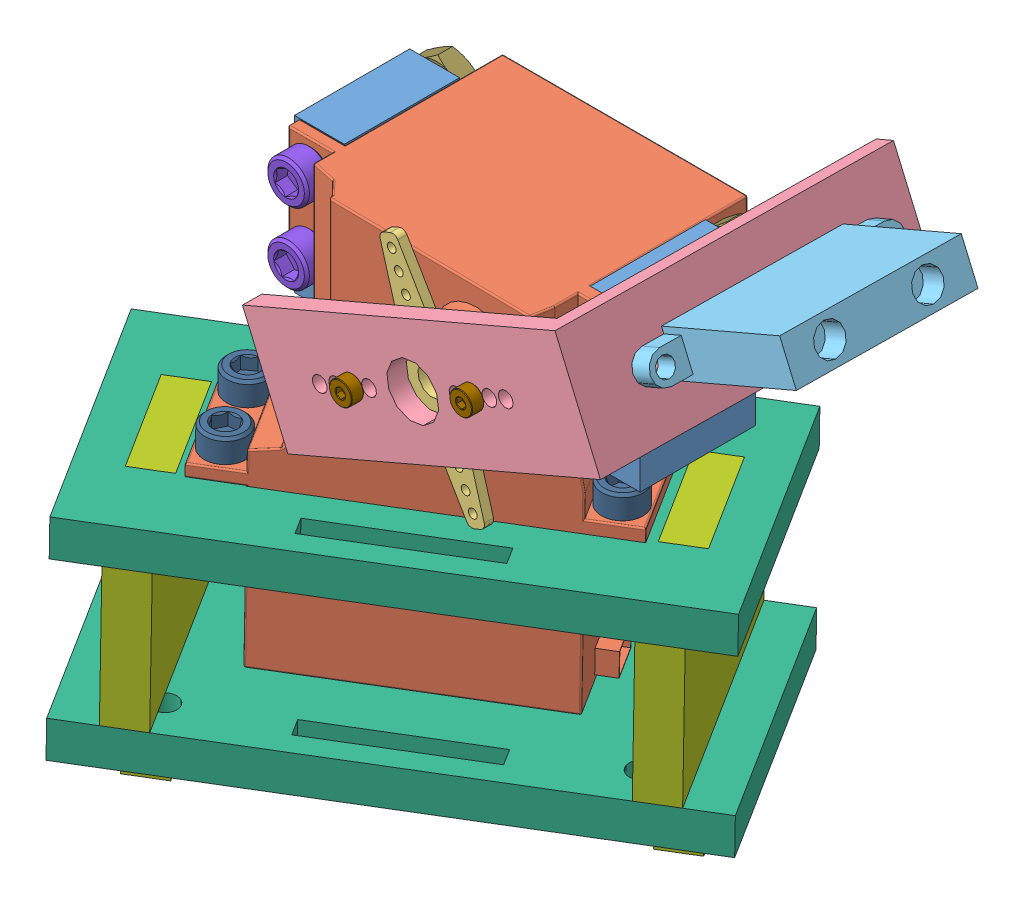
SolidWorks assembly Pan Tilt, configuration Default. Lengths in mm.
Overall size (116.12 101.24 80.83).
39 component instances, 12 part files, 90 mates.
Components (placement in the parent):
- Tilt Servo Mount-1: Tilt Servo Mount [Default] at (3.2915 33.3562 50.9879) size (57.15 25.37 39.37)
- servo motor-1: servo motor [Default] at (11.6735 58.7242 70.0379) x (1 0 0) z (0 -1 0) size (55.24 41.08 20.19)
- Servo Horn-1: Servo Horn [Default] at (42.5865 48.6277 85.0397) x (0.916481 0.399893 0.01215) z (0.399858 -0.916562 0.005301) size (38 5.5 38)
- Sensor Mount-1: Sensor Mount [Default] at (21.6417 29.1053 86.2622) x (0.916481 0.399893 0.01215) z (-0.013256 0 0.999912) size (57.15 19.05 55.24)
- Distance Sensor-1: Distance Sensor [Default] at (71.7666 57.4815 75.0766) x (0.013256 0 -0.999912) z (0.916481 0.399893 0.01215) size (41.7 7 21.62)
- Servo Horn-2: Servo Horn [Default] at (31.8665 31.8562 60.5128) size (38 5.5 38)
- servo motor-2: servo motor [Default] at (0.1726 17.2654 68.5885) x (0.845413 -0.013256 -0.533948) z (0.533995 0 0.845487) size (55.24 41.08 20.19)
- Base Plate-1: Base Plate [Default] at (10.8879 11.2334 85.7042) x (0.845413 -0.013256 -0.533948) z (0.533995 0 0.845487) size (82.55 6.03 43.18)
- Side Plate-1: Side Plate [Short] at (4.6513 11.4275 103.237) x (-0.011208 -0.999912 0.007079) z (0.533995 0 0.845487) size (44.13 6.03 43.18)
- Side Plate-2: Side Plate [Short] at (58.6571 10.5806 69.1279) x (-0.011208 -0.999912 0.007079) z (0.533995 0 0.845487) size (44.13 6.03 43.18)
- Base Plate-2: Base Plate [Breadclamp] at (10.5641 -17.6565 85.9087) x (0.845413 -0.013256 -0.533948) z (0.533995 0 0.845487) size (82.55 6.03 43.18)
- 91251A199_Black-Oxide Alloy Steel Socket Head Screw-1: 91251A199_Black-Oxide Alloy Steel Socket Head Screw [91251A199] at (8.1175 42.7222 61.4599) x (0.938495 -0.345293 0) z (0 0 1) size (6.86 6.86 30.18)
- 91251A199_Black-Oxide Alloy Steel Socket Head Screw-2: 91251A199_Black-Oxide Alloy Steel Socket Head Screw [91251A199] at (55.7425 42.7222 61.4599) x (0.998866 0.047604 0) z (0 0 1) size (6.86 6.86 30.18)
- 91251A199_Black-Oxide Alloy Steel Socket Head Screw-3: 91251A199_Black-Oxide Alloy Steel Socket Head Screw [91251A199] at (55.7425 54.5332 61.4599) x (0.697496 -0.716589 0) z (0 0 1) size (6.86 6.86 30.18)
- 91290A013_Black-Oxide Alloy Steel Socket Head Screw-2: 91290A013_Black-Oxide Alloy Steel Socket Head Screw [91290A013] at (52.6323 53.0265 87.8482) x (0.999912 0 0.013256) z (-0.013256 0 0.999912) size (3.8 3.8 8.09)
- 91290A013_Black-Oxide Alloy Steel Socket Head Screw-6: 91290A013_Black-Oxide Alloy Steel Socket Head Screw [91290A013] at (32.4697 44.2288 87.5808) x (0.999912 0 0.013256) z (-0.013256 0 0.999912) size (3.8 3.8 8.09)
- 91251A199_Black-Oxide Alloy Steel Socket Head Screw-5: 91251A199_Black-Oxide Alloy Steel Socket Head Screw [91251A199] at (8.1175 54.5332 61.4599) x (0.996492 -0.083694 0) z (0 0 1) size (6.86 6.86 30.18)
- 91251A190_Black-Oxide Alloy Steel Socket Head Screw-1: 91251A190_Black-Oxide Alloy Steel Socket Head Screw [91251A190] at (5.7172 17.843 84.013) x (0.091869 0.00602 0.995753) z (0.011208 0.999912 -0.007079) size (6.86 6.86 11.02)
- 91251A190_Black-Oxide Alloy Steel Socket Head Screw-2: 91251A190_Black-Oxide Alloy Steel Socket Head Screw [91251A190] at (-0.5898 17.843 74.0269) x (-0.38152 0.01082 0.924297) z (0.011208 0.999912 -0.007079) size (6.86 6.86 11.02)
- 91251A190_Black-Oxide Alloy Steel Socket Head Screw-3: 91251A190_Black-Oxide Alloy Steel Socket Head Screw [91251A190] at (39.673 17.2116 48.5976) x (0.655804 -0.002006 0.754928) z (0.011208 0.999912 -0.007079) size (6.86 6.86 11.02)
- 91251A190_Black-Oxide Alloy Steel Socket Head Screw-4: 91251A190_Black-Oxide Alloy Steel Socket Head Screw [91251A190] at (45.98 17.2116 58.5837) x (0.997237 -0.010658 0.073517) z (0.011208 0.999912 -0.007079) size (6.86 6.86 11.02)
- 91290A013_Black-Oxide Alloy Steel Socket Head Screw-7: 91290A013_Black-Oxide Alloy Steel Socket Head Screw [91290A013] at (14.8665 34.5312 60.5129) x (-0.912425 0 -0.409244) z (0 1 0) size (3.8 3.8 8.09)
- 91290A013_Black-Oxide Alloy Steel Socket Head Screw-8: 91290A013_Black-Oxide Alloy Steel Socket Head Screw [91290A013] at (48.8665 34.5312 60.5129) x (-0.885375 0 0.464877) z (0 1 0) size (3.8 3.8 8.09)
- 91290A013_Black-Oxide Alloy Steel Socket Head Screw-9: 91290A013_Black-Oxide Alloy Steel Socket Head Screw [91290A013] at (31.8665 34.5312 77.5128) x (-0.492181 0 -0.870493) z (0 1 0) size (3.8 3.8 8.09)
- 91290A013_Black-Oxide Alloy Steel Socket Head Screw-10: 91290A013_Black-Oxide Alloy Steel Socket Head Screw [91290A013] at (31.8665 34.5312 43.5129) x (-0.733437 0 -0.679757) z (0 1 0) size (3.8 3.8 8.09)
- 90592A004_Steel Hex Nut-1: 90592A004_Steel Hex Nut [90592A004] at (52.6784 53.0265 84.3735) x (0.82097 -0.570868 0.010884) z (-0.570818 -0.821042 -0.007568) size (4 1.91 4.62)
- 90592A004_Steel Hex Nut-2: 90592A004_Steel Hex Nut [90592A004] at (32.5158 44.2288 84.1062) x (-0.196615 -0.980477 -0.002607) z (-0.980391 0.196632 -0.012998) size (4 1.91 4.62)
- 90592A004_Steel Hex Nut-3: 90592A004_Steel Hex Nut [90592A004] at (48.8665 31.0562 60.5129) x (0.996971 0 -0.077772) z (-0.077772 0 -0.996971) size (4 1.91 4.62)
- 90592A004_Steel Hex Nut-4: 90592A004_Steel Hex Nut [90592A004] at (31.8665 31.0562 77.5128) x (1 0 0) z (0 0 -1) size (4 1.91 4.62)
- 90592A004_Steel Hex Nut-5: 90592A004_Steel Hex Nut [90592A004] at (14.8665 31.0562 60.5128) size (4 1.91 4.62)
- 90592A004_Steel Hex Nut-6: 90592A004_Steel Hex Nut [90592A004] at (31.8665 31.0562 43.5129) x (0.96042 0 0.278555) z (-0.278555 0 0.96042) size (4 1.91 4.62)
- 90480A009_Low-Strength Steel Hex Nut-1: 90480A009_Low-Strength Steel Hex Nut [90480A009] at (55.9965 54.7872 49.4004) x (0.990497 0.137534 0) z (0.137534 -0.990497 0) size (8.73 3.79 10.08)
- 90480A009_Low-Strength Steel Hex Nut-2: 90480A009_Low-Strength Steel Hex Nut [90480A009] at (55.9965 42.4682 49.4004) x (0.856607 -0.515969 0) z (-0.515969 -0.856607 0) size (8.73 3.79 10.08)
- 90480A009_Low-Strength Steel Hex Nut-3: 90480A009_Low-Strength Steel Hex Nut [90480A009] at (7.7365 54.7872 49.4004) x (0.999481 0.03222 0) z (0.03222 -0.999481 0) size (8.73 3.79 10.08)
- 90480A009_Low-Strength Steel Hex Nut-4: 90480A009_Low-Strength Steel Hex Nut [90480A009] at (7.7365 42.4682 49.4004) x (0.568434 -0.822729 0) z (-0.822729 -0.568434 0) size (8.73 3.79 10.08)
- 90480A009_Low-Strength Steel Hex Nut-5: 90480A009_Low-Strength Steel Hex Nut [90480A009] at (39.5816 9.0619 48.6553) x (0.997702 -0.011656 -0.066739) z (0.066815 0.006315 0.997745) size (8.73 3.79 10.08)
- 90480A009_Low-Strength Steel Hex Nut-6: 90480A009_Low-Strength Steel Hex Nut [90480A009] at (-0.8224 9.6949 74.0988) x (0.999937 -0.011208 0.000051) z (0.000029 0.007079 0.999975) size (8.73 3.79 10.08)
- 90480A009_Low-Strength Steel Hex Nut-7: 90480A009_Low-Strength Steel Hex Nut [90480A009] at (45.8887 9.0619 58.6414) x (0.999937 -0.011208 0.000051) z (0.000029 0.007079 0.999975) size (8.73 3.79 10.08)
- 90480A009_Low-Strength Steel Hex Nut-8: 90480A009_Low-Strength Steel Hex Nut [90480A009] at (5.6259 9.6932 84.0707) x (0.999937 -0.011208 0.000051) z (0.000029 0.007079 0.999975) size (8.73 3.79 10.08)
Mates (geometry in assembly coordinates):
- Coincident1: coincident anti-aligned: plane of Tilt Servo Mount-1 through (52.1865 38.5312 70.0379) normal (-1 0 0); plane of servo motor-1 through (52.1865 38.5312 11.4627) normal (1 0 0)
- Coincident2: coincident anti-aligned: plane of Tilt Servo Mount-1 through (11.5465 38.5312 70.0379) normal (0 1 0); plane of servo motor-1 through (31.8662 38.5312 11.4627) normal (0 -1 0)
- Coincident3: coincident anti-aligned: plane of Tilt Servo Mount-1 through (3.2915 33.3562 70.0379) normal (0 0 1); plane of servo motor-1 through (31.8662 38.5312 70.0379) normal (0 0 -1)
- Concentric1: concentric aligned: cylinder of servo motor-1 through (42.5865 48.6277 85.0397) axis (0.013256 0 -0.999912) radius 2.921; cylinder of Servo Horn-1 through (42.5666 48.6277 86.5396) axis (0.013256 0 -0.999912) radius 2.413
- Coincident4: coincident anti-aligned: plane of servo motor-1 through (4.1278 48.6263 84.5299) normal (-0.013256 0 0.999912); plane of Servo Horn-1 through (42.5865 48.6277 85.0397) normal (0.013256 0 -0.999912)
- Coincident5: coincident anti-aligned: plane of Sensor Mount-1; plane of Distance Sensor-1
- Concentric2: concentric aligned: cylinder of Sensor Mount-1 through (70.8068 60.6894 41.8885) axis (-0.916481 -0.399893 -0.01215) radius 1.5875; cylinder of Distance Sensor-1 through (73.7166 61.9591 41.9271) axis (-0.916481 -0.399893 -0.01215) radius 1.524
- Concentric3: concentric aligned: cylinder of Sensor Mount-1 through (70.3203 60.6894 78.5883) axis (-0.916481 -0.399893 -0.01215) radius 1.5875; cylinder of Distance Sensor-1 through (73.2301 61.9591 78.6269) axis (-0.916481 -0.399893 -0.01215) radius 1.524
- Concentric4: concentric aligned: cylinder of Servo Horn-1 through (35.2348 45.4285 86.4424) axis (0.013256 0 -0.999912) radius 0.75; cylinder of Sensor Mount-1 through (35.1927 45.4285 89.6171) axis (0.013256 0 -0.999912) radius 1.25
- Concentric5: concentric aligned: cylinder of Servo Horn-1 through (49.8985 51.8268 86.6368) axis (0.013256 0 -0.999912) radius 0.75; cylinder of Sensor Mount-1 through (49.8564 51.8268 89.8115) axis (0.013256 0 -0.999912) radius 1.25
- Coincident6: coincident anti-aligned: plane of Servo Horn-1 through (42.5666 48.6277 86.5396) normal (-0.013256 0 0.999912); plane of Sensor Mount-1 through (21.6417 29.1053 86.2622) normal (0.013256 0 -0.999912)
- Concentric8: concentric aligned: cylinder of Servo Horn-2 through (31.8665 33.3562 60.5128) axis (0 -1 0) radius 2.413; cylinder of servo motor-2 through (31.8665 31.8562 60.5128) axis (0 -1 0) radius 2.921
- Coincident7: coincident anti-aligned: plane of Servo Horn-2 through (31.8665 31.8562 60.5128) normal (0 -1 0); plane of servo motor-2 through (-0.652 31.8562 81.0526) normal (0 1 0)
- Concentric9: concentric aligned: cylinder of Tilt Servo Mount-1 through (39.8665 50.879 60.5129) axis (0 -1 0) radius 1.25; cylinder of Servo Horn-2 through (39.8665 33.3562 60.5128) axis (0 -1 0) radius 0.75
- Concentric10: concentric aligned: cylinder of Tilt Servo Mount-1 through (31.8665 50.879 52.5128) axis (0 -1 0) radius 1.25; cylinder of Servo Horn-2 through (31.8665 33.3562 52.5128) axis (0 -1 0) radius 0.75
- Coincident11: coincident anti-aligned: plane of Tilt Servo Mount-1 through (3.2915 33.3562 70.0379) normal (0 -1 0); plane of Servo Horn-2 through (31.8665 33.3562 60.5128) normal (0 1 0)
- Coincident12: coincident anti-aligned: plane of servo motor-2 through (28.0267 16.9977 74.8796) normal (-0.011208 -0.999912 0.007079); plane of Base Plate-1 through (10.9555 17.2654 85.6615) normal (0.011208 0.999912 -0.007079)
- Parallel8: parallel aligned: plane of servo motor-2 through (10.299 -41.3047 86.0761) normal (-0.845413 0.013256 0.533948); plane of Base Plate-1 through (-0.6226 17.5432 106.568) normal (-0.845413 0.013256 0.533948)
- Coincident14: coincident anti-aligned: plane of servo motor-2 through (27.3702 -41.5723 75.2942) normal (0.533995 0 0.845487); plane of Base Plate-1 through (10.9555 17.2654 85.6615) normal (-0.533995 0 -0.845487)
- Coincident15: coincident anti-aligned: plane of servo motor-2 through (10.299 -41.3047 86.0761) normal (-0.845413 0.013256 0.533948); plane of Base Plate-1 through (10.9555 17.2654 85.6615) normal (0.845413 -0.013256 -0.533948)
- Coincident17: coincident aligned: plane of Base Plate-1 through (10.9555 17.2654 85.6615) normal (0.011208 0.999912 -0.007079); plane of Side Plate-1 through (3.3762 17.3795 89.7725) normal (0.011208 0.999912 -0.007079)
- Coincident18: coincident anti-aligned: plane of Base Plate-1 through (-1.7237 17.4594 92.9935) normal (-0.533995 0 -0.845487); plane of Side Plate-1 through (3.3086 11.3475 89.8152) normal (0.533995 0 0.845487)
- Coincident21: coincident anti-aligned: plane of Base Plate-1 through (-11.8964 17.4594 76.887) normal (0.845413 -0.013256 -0.533948); plane of Side Plate-1 through (4.6513 11.4275 103.237) normal (-0.845413 0.013256 0.533948)
- Coincident22: coincident anti-aligned: plane of Base Plate-1 through (47.2094 16.5326 39.5568) normal (-0.845413 0.013256 0.533948); plane of Side Plate-2 through (63.7571 10.5007 65.9068) normal (0.845413 -0.013256 -0.533948)
- Coincident23: coincident aligned: plane of Base Plate-1 through (10.9555 17.2654 85.6615) normal (0.011208 0.999912 -0.007079); plane of Side Plate-2 through (57.382 16.5326 55.6633) normal (0.011208 0.999912 -0.007079)
- Coincident24: coincident anti-aligned: plane of Base Plate-1 through (57.382 16.5326 55.6633) normal (-0.533995 0 -0.845487); plane of Side Plate-2 through (57.3144 10.5007 55.706) normal (0.533995 0 0.845487)
- Coincident25: coincident anti-aligned: plane of Side Plate-1 through (9.495 -11.5105 100.1778) normal (-0.011208 -0.999912 0.007079); plane of Base Plate-2 through (10.6317 -11.6246 85.866) normal (0.011208 0.999912 -0.007079)
- Coincident26: coincident anti-aligned: plane of Side Plate-1 through (9.7513 11.3475 100.016) normal (0.845413 -0.013256 -0.533948); plane of Base Plate-2 through (-7.1202 -11.5105 73.8705) normal (-0.845413 0.013256 0.533948)
- Coincident27: coincident anti-aligned: plane of Side Plate-1 through (3.0524 -11.5105 89.977) normal (0.533995 0 0.845487); plane of Base Plate-2 through (-2.0476 -11.4305 93.1981) normal (-0.533995 0 -0.845487)
- Coincident28: coincident aligned: plane of Side Plate-1 through (2.8816 -26.7492 90.0849) normal (-0.011208 -0.999912 0.007079); plane of Base Plate-3 through (10.4609 -26.8632 85.9739) normal (-0.011208 -0.999912 0.007079)
- Concentric11: concentric aligned: cylinder of Base Plate-2 through (6.2678 -23.258 94.7056) axis (0.011208 0.999912 -0.007079) radius 2.0193; cylinder of Base Plate-3 through (6.1646 -32.4647 94.7708) axis (0.011208 0.999912 -0.007079) radius 2.0193
- Coincident29: coincident aligned: cylinder of Base Plate-2 through (-10.0084 -23.258 68.9352) axis (0.011208 0.999912 -0.007079) radius 2.0193; circle of Base Plate-3
- Concentric12: concentric anti-aligned: circle of servo motor-1; circle of 91251A199_Black-Oxide Alloy Steel Socket Head Screw-5
- Concentric13: concentric anti-aligned: cylinder of servo motor-1 through (8.1175 42.7222 62.1711) axis (0 0 1) radius 2.159; cylinder of 91251A199_Black-Oxide Alloy Steel Socket Head Screw-1 through (8.1175 42.7222 46.6771) axis (0 0 -1) radius 3.429
- Concentric14: concentric anti-aligned: cylinder of servo motor-1 through (55.7425 42.7222 62.1711) axis (0 0 1) radius 2.159; cylinder of 91251A199_Black-Oxide Alloy Steel Socket Head Screw-2 through (55.7425 42.7222 46.6771) axis (0 0 -1) radius 3.429
- Concentric15: concentric anti-aligned: cylinder of servo motor-1 through (55.7425 54.5332 62.1711) axis (0 0 1) radius 2.159; cylinder of 91251A199_Black-Oxide Alloy Steel Socket Head Screw-3 through (55.7425 54.5332 46.6771) axis (0 0 -1) radius 3.429
- Coincident30: coincident: plane of servo motor-1 through (31.8662 38.5312 72.0771) normal (0 0 1); point of 91251A199_Black-Oxide Alloy Steel Socket Head Screw-5
- Coincident31: coincident anti-aligned: plane of servo motor-1 through (31.8662 38.5312 72.0771) normal (0 0 1); plane of 91251A199_Black-Oxide Alloy Steel Socket Head Screw-1 through (9.1576 45.5493 72.0771) normal (0 0 -1)
- Coincident32: coincident anti-aligned: plane of servo motor-1 through (31.8662 38.5312 72.0771) normal (0 0 1); plane of 91251A199_Black-Oxide Alloy Steel Socket Head Screw-3 through (57.9011 56.6343 72.0771) normal (0 0 -1)
- Coincident33: coincident anti-aligned: plane of servo motor-1 through (31.8662 38.5312 72.0771) normal (0 0 1); plane of 91251A199_Black-Oxide Alloy Steel Socket Head Screw-2 through (55.5991 45.7312 72.0771) normal (0 0 -1)
- Concentric16: concentric aligned: cylinder of Sensor Mount-1 through (32.4432 44.2288 89.5807) axis (0.013256 0 -0.999912) radius 1.25; cylinder of 91290A013_Black-Oxide Alloy Steel Socket Head Screw-6 through (32.5228 44.2288 83.5812) axis (0.013256 0 -0.999912) radius 1.9
- Concentric17: concentric aligned: cylinder of Sensor Mount-1 through (52.6058 53.0265 89.848) axis (0.013256 0 -0.999912) radius 1.25; cylinder of 91290A013_Black-Oxide Alloy Steel Socket Head Screw-2 through (52.6854 53.0265 83.8485) axis (0.013256 0 -0.999912) radius 1.9
- Coincident34: coincident anti-aligned: plane of Sensor Mount-1 through (21.5996 29.1053 89.4369) normal (-0.013256 0 0.999912); plane of 91290A013_Black-Oxide Alloy Steel Socket Head Screw-2 through (52.6058 54.8265 89.848) normal (0.013256 0 -0.999912)
- Coincident35: coincident anti-aligned: plane of Sensor Mount-1 through (21.5996 29.1053 89.4369) normal (-0.013256 0 0.999912); plane of 91290A013_Black-Oxide Alloy Steel Socket Head Screw-6 through (32.4432 46.0288 89.5807) normal (0.013256 0 -0.999912)
- Concentric23: concentric anti-aligned: cylinder of Servo Horn-2 through (31.8665 33.3562 49.5128) axis (0 -1 0) radius 0.75; cylinder of 91290A013_Black-Oxide Alloy Steel Socket Head Screw-5 through (31.8665 37.9562 50.5129) axis (0 1 0) radius 1.9
- Coincident36: coincident anti-aligned: plane of Servo Horn-2 through (31.8665 31.8562 60.5128) normal (0 -1 0); circle of 91290A013_Black-Oxide Alloy Steel Socket Head Screw-5
- Concentric24: concentric anti-aligned: cylinder of servo motor-2 through (-0.6839 9.4465 74.0864) axis (0.011208 0.999912 -0.007079) radius 2.159; cylinder of 91251A190_Black-Oxide Alloy Steel Socket Head Screw-2 through (-0.6487 12.5856 74.0642) axis (-0.011208 -0.999912 0.007079) radius 3.429
- Concentric25: concentric anti-aligned: cylinder of servo motor-2 through (5.6231 9.4465 84.0724) axis (0.011208 0.999912 -0.007079) radius 2.159; cylinder of 91251A190_Black-Oxide Alloy Steel Socket Head Screw-1 through (5.6583 12.5856 84.0502) axis (-0.011208 -0.999912 0.007079) radius 3.429
- Concentric26: concentric anti-aligned: cylinder of servo motor-2 through (39.5789 8.8151 48.6571) axis (0.011208 0.999912 -0.007079) radius 2.159; cylinder of 91251A190_Black-Oxide Alloy Steel Socket Head Screw-3 through (39.6141 11.9543 48.6349) axis (-0.011208 -0.999912 0.007079) radius 3.429
- Concentric27: concentric anti-aligned: cylinder of servo motor-2 through (45.8859 8.8151 58.6431) axis (0.011208 0.999912 -0.007079) radius 2.159; cylinder of 91251A190_Black-Oxide Alloy Steel Socket Head Screw-4 through (45.9211 11.9543 58.6209) axis (-0.011208 -0.999912 0.007079) radius 3.429
- Coincident40: coincident anti-aligned: plane of servo motor-2 through (28.0496 19.0368 74.8652) normal (0.011208 0.999912 -0.007079); circle of 91251A190_Black-Oxide Alloy Steel Socket Head Screw-4
- Coincident41: coincident anti-aligned: plane of servo motor-2 through (28.0496 19.0368 74.8652) normal (0.011208 0.999912 -0.007079); circle of 91251A190_Black-Oxide Alloy Steel Socket Head Screw-3
- Coincident42: coincident anti-aligned: plane of servo motor-2 through (28.0496 19.0368 74.8652) normal (0.011208 0.999912 -0.007079); circle of 91251A190_Black-Oxide Alloy Steel Socket Head Screw-2
- Coincident43: coincident anti-aligned: plane of servo motor-2 through (28.0496 19.0368 74.8652) normal (0.011208 0.999912 -0.007079); circle of 91251A190_Black-Oxide Alloy Steel Socket Head Screw-1
- Concentric28: concentric anti-aligned: cylinder of Tilt Servo Mount-1 through (31.8665 36.5312 43.5129) axis (0 1 0) radius 2; cylinder of 91290A013_Black-Oxide Alloy Steel Socket Head Screw-10 through (31.8665 30.5312 43.5129) axis (0 -1 0) radius 1.9
- Coincident45: coincident anti-aligned: plane of Tilt Servo Mount-1 through (31.8665 36.5312 43.5129) normal (0 1 0); plane of 91290A013_Black-Oxide Alloy Steel Socket Head Screw-10 through (30.6429 36.5312 44.833) normal (0 -1 0)
- Concentric29: concentric anti-aligned: cylinder of Tilt Servo Mount-1 through (48.8665 36.5312 60.5129) axis (0 1 0) radius 2; cylinder of 91290A013_Black-Oxide Alloy Steel Socket Head Screw-8 through (48.8665 30.5312 60.5129) axis (0 -1 0) radius 1.9
- Concentric30: concentric anti-aligned: cylinder of Tilt Servo Mount-1 through (31.8665 36.5312 77.5128) axis (0 1 0) radius 2; cylinder of 91290A013_Black-Oxide Alloy Steel Socket Head Screw-9 through (31.8665 30.5312 77.5128) axis (0 -1 0) radius 1.9
- Concentric31: concentric anti-aligned: cylinder of Tilt Servo Mount-1 through (14.8665 36.5312 60.5129) axis (0 1 0) radius 2; cylinder of 91290A013_Black-Oxide Alloy Steel Socket Head Screw-7 through (14.8665 30.5312 60.5129) axis (0 -1 0) radius 1.9
- Coincident46: coincident anti-aligned: plane of Tilt Servo Mount-1 through (14.8665 36.5312 60.5129) normal (0 1 0); plane of 91290A013_Black-Oxide Alloy Steel Socket Head Screw-7 through (14.1298 36.5312 62.1552) normal (0 -1 0)
- Coincident47: coincident anti-aligned: plane of Tilt Servo Mount-1 through (31.8665 36.5312 77.5128) normal (0 1 0); plane of 91290A013_Black-Oxide Alloy Steel Socket Head Screw-9 through (30.2996 36.5312 78.3988) normal (0 -1 0)
- Coincident48: coincident anti-aligned: plane of Tilt Servo Mount-1 through (48.8665 36.5312 60.5129) normal (0 1 0); plane of 91290A013_Black-Oxide Alloy Steel Socket Head Screw-8 through (49.7032 36.5312 62.1065) normal (0 -1 0)
- Concentric32: concentric aligned: circle of 91290A013_Black-Oxide Alloy Steel Socket Head Screw-8; circle of 90592A004_Steel Hex Nut-3
- Coincident49: coincident anti-aligned: plane of Servo Horn-2 through (31.8665 31.8562 60.5128) normal (0 -1 0); plane of 90592A004_Steel Hex Nut-3 through (46.9623 31.8562 61.8196) normal (0 1 0)
- Concentric33: concentric aligned: circle of Tilt Servo Mount-1; circle of 90592A004_Steel Hex Nut-6
- Coincident51: coincident anti-aligned: plane of Servo Horn-2 through (31.8665 31.8562 60.5128) normal (0 -1 0); plane of 90592A004_Steel Hex Nut-6 through (30.2673 31.8562 41.8468) normal (0 1 0)
- Concentric34: concentric aligned: circle of Servo Horn-2; circle of 90592A004_Steel Hex Nut-5
- Coincident52: coincident anti-aligned: plane of Servo Horn-2 through (31.8665 31.8562 60.5128) normal (0 -1 0); plane of 90592A004_Steel Hex Nut-5 through (12.8665 31.8562 59.3581) normal (0 1 0)
- Concentric35: concentric aligned: circle of 91290A013_Black-Oxide Alloy Steel Socket Head Screw-9; circle of 90592A004_Steel Hex Nut-4
- Coincident54: coincident anti-aligned: plane of Servo Horn-2 through (31.8665 31.8562 60.5128) normal (0 -1 0); plane of 90592A004_Steel Hex Nut-4 through (29.8665 31.8562 78.6675) normal (0 1 0)
- Concentric36: concentric anti-aligned: cylinder of 91290A013_Black-Oxide Alloy Steel Socket Head Screw-6 through (32.5228 44.2288 83.5812) axis (0.013256 0 -0.999912) radius 1.9; circle of 90592A004_Steel Hex Nut-2
- Concentric37: concentric anti-aligned: cylinder of 91290A013_Black-Oxide Alloy Steel Socket Head Screw-2 through (52.6854 53.0265 83.8485) axis (0.013256 0 -0.999912) radius 1.9; circle of 90592A004_Steel Hex Nut-1
- Coincident55: coincident anti-aligned: plane of Servo Horn-1 through (42.5865 48.6277 85.0397) normal (0.013256 0 -0.999912); plane of 90592A004_Steel Hex Nut-1 through (51.685 55.1163 85.1604) normal (-0.013256 0 0.999912)
- Coincident56: coincident anti-aligned: plane of Servo Horn-1 through (42.5865 48.6277 85.0397) normal (0.013256 0 -0.999912); plane of 90592A004_Steel Hex Nut-2 through (34.0305 45.9627 84.9263) normal (-0.013256 0 0.999912)
- Concentric38: concentric aligned: circle of Tilt Servo Mount-1; circle of 90480A009_Low-Strength Steel Hex Nut-1
- Concentric39: concentric aligned: circle of Tilt Servo Mount-1; circle of 90480A009_Low-Strength Steel Hex Nut-2
- Concentric40: concentric aligned: circle of Tilt Servo Mount-1; circle of 90480A009_Low-Strength Steel Hex Nut-4
- Concentric41: concentric aligned: circle of Tilt Servo Mount-1; circle of 90480A009_Low-Strength Steel Hex Nut-3
- Coincident57: coincident anti-aligned: plane of Tilt Servo Mount-1 through (3.2915 33.3562 50.9879) normal (0 0 -1); plane of 90480A009_Low-Strength Steel Hex Nut-3 through (3.2919 57.1657 50.9879) normal (0 0 1)
- Coincident58: coincident anti-aligned: plane of Tilt Servo Mount-1 through (3.2915 33.3562 50.9879) normal (0 0 -1); plane of 90480A009_Low-Strength Steel Hex Nut-4 through (7.3286 47.4926 50.9879) normal (0 0 1)
- Coincident59: coincident anti-aligned: plane of Tilt Servo Mount-1 through (3.2915 33.3562 50.9879) normal (0 0 -1); plane of 90480A009_Low-Strength Steel Hex Nut-1 through (51.3257 56.6833 50.9879) normal (0 0 1)
- Coincident60: coincident anti-aligned: plane of Tilt Servo Mount-1 through (3.2915 33.3562 50.9879) normal (0 0 -1); plane of 90480A009_Low-Strength Steel Hex Nut-2 through (53.5573 46.8798 50.9879) normal (0 0 1)
- Concentric42: concentric anti-aligned: cylinder of 91251A190_Black-Oxide Alloy Steel Socket Head Screw-3 through (39.6141 11.9543 48.6349) axis (-0.011208 -0.999912 0.007079) radius 3.429; circle of 90480A009_Low-Strength Steel Hex Nut-5
- Coincident61: coincident anti-aligned: plane of Base Plate-1 through (10.8879 11.2334 85.7042) normal (-0.011208 -0.999912 0.007079); plane of 90480A009_Low-Strength Steel Hex Nut-5 through (35.0754 10.6842 46.4206) normal (0.011208 0.999912 -0.007079)
- Concentric43: concentric anti-aligned: cylinder of 91251A190_Black-Oxide Alloy Steel Socket Head Screw-4 through (45.9211 11.9543 58.6209) axis (-0.011208 -0.999912 0.007079) radius 3.429; circle of 90480A009_Low-Strength Steel Hex Nut-7
- Coincident62: coincident anti-aligned: plane of Base Plate-1 through (10.8879 11.2334 85.7042) normal (-0.011208 -0.999912 0.007079); plane of 90480A009_Low-Strength Steel Hex Nut-7 through (41.541 10.6803 56.1095) normal (0.011208 0.999912 -0.007079)
- Concentric44: concentric aligned: circle of Base Plate-1; circle of 90480A009_Low-Strength Steel Hex Nut-6
- Coincident63: coincident anti-aligned: plane of Base Plate-1 through (10.8879 11.2334 85.7042) normal (-0.011208 -0.999912 0.007079); plane of 90480A009_Low-Strength Steel Hex Nut-6 through (-5.1701 11.3133 71.5669) normal (0.011208 0.999912 -0.007079)
- Concentric45: concentric anti-aligned: cylinder of 91251A190_Black-Oxide Alloy Steel Socket Head Screw-1 through (5.6583 12.5856 84.0502) axis (-0.011208 -0.999912 0.007079) radius 3.429; circle of 90480A009_Low-Strength Steel Hex Nut-8
- Coincident64: coincident anti-aligned: plane of Base Plate-1 through (10.8879 11.2334 85.7042) normal (-0.011208 -0.999912 0.007079); plane of 90480A009_Low-Strength Steel Hex Nut-8 through (1.2782 11.3117 81.5388) normal (0.011208 0.999912 -0.007079)
